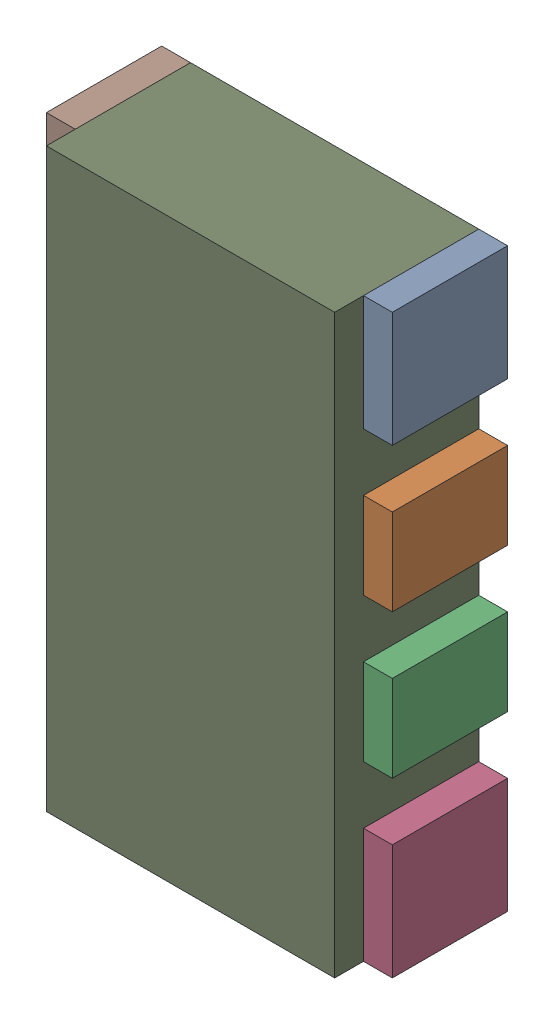
SolidWorks assembly RN5, configuration Default. Lengths in mm.
Overall size (1.2 2 0.5).
18 component instances, 3 part files, 0 mates.
Components (placement in the parent):
- 791587232-1: 791587232 [Default] at (108.9 31.2 0) size (0.1 0.4 0.4)
  - Extruded_10-1: Extruded_10 [Default] at origin size (0.1 0.4 0.4)
- 836750576-1: 836750576 [Default] at (108.9 30.65 0) size (0.1 0.3 0.4)
  - Extruded_14-1: Extruded_14 [Default] at origin size (0.1 0.3 0.4)
- 836750576-2: 836750576 [Default] at (108.9 30.15 0) size (0.1 0.3 0.4)
  - Extruded_14-1: Extruded_14 [Default] at origin size (0.1 0.3 0.4)
- 791587232-2: 791587232 [Default] at (108.9 29.6 0) size (0.1 0.4 0.4)
  - Extruded_10-1: Extruded_10 [Default] at origin size (0.1 0.4 0.4)
- 791587232-3: 791587232 [Default] at (107.8 29.6 0) size (0.1 0.4 0.4)
  - Extruded_10-1: Extruded_10 [Default] at origin size (0.1 0.4 0.4)
- 836750576-3: 836750576 [Default] at (107.8 30.15 0) size (0.1 0.3 0.4)
  - Extruded_14-1: Extruded_14 [Default] at origin size (0.1 0.3 0.4)
- 836750576-4: 836750576 [Default] at (107.8 30.65 0) size (0.1 0.3 0.4)
  - Extruded_14-1: Extruded_14 [Default] at origin size (0.1 0.3 0.4)
- 791587232-4: 791587232 [Default] at (107.8 31.2 0) size (0.1 0.4 0.4)
  - Extruded_10-1: Extruded_10 [Default] at origin size (0.1 0.4 0.4)
- 836750320-1: 836750320 [Default] at (108.35 30.4 0) size (1 2 0.5)
  - Extruded_15-1: Extruded_15 [Default] at origin size (1 2 0.5)
